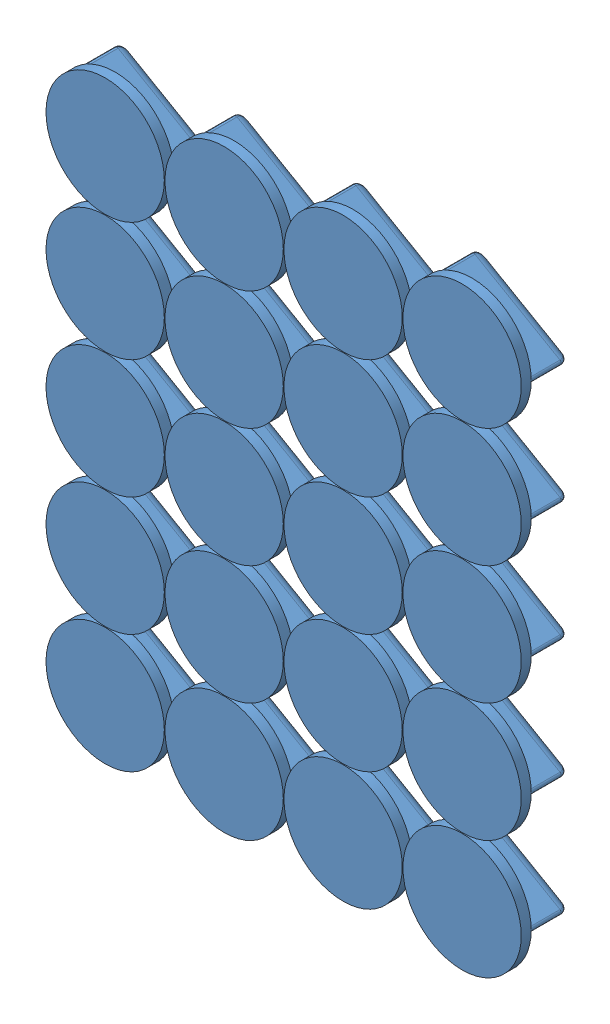
SolidWorks assembly Impression des bouton triangle, configuration Défaut. Lengths in mm.
Overall size (64.88 59.43 5).
20 component instances, 1 part files, 0 mates.
Components (placement in the parent):
- BoutonV2_PourImpression-1: BoutonV2_PourImpression [Default] at (-46.1693 10.9787 -2.5) size (19 11.83 5)
- BoutonV2_PourImpression-2: BoutonV2_PourImpression [Default] at (-46.1693 -0.9213 -2.5) size (19 11.83 5)
- BoutonV2_PourImpression-3: BoutonV2_PourImpression [Default] at (-46.1693 -12.8213 -2.5) size (19 11.83 5)
- BoutonV2_PourImpression-4: BoutonV2_PourImpression [Default] at (-46.1693 -24.7213 -2.5) size (19 11.83 5)
- BoutonV2_PourImpression-5: BoutonV2_PourImpression [Default] at (-46.1693 -36.6213 -2.5) size (19 11.83 5)
- BoutonV2_PourImpression-6: BoutonV2_PourImpression [Default] at (-58.0693 -36.6213 -2.5) size (19 11.83 5)
- BoutonV2_PourImpression-7: BoutonV2_PourImpression [Default] at (-69.9693 -36.6213 -2.5) size (19 11.83 5)
- BoutonV2_PourImpression-8: BoutonV2_PourImpression [Default] at (-81.8693 -36.6213 -2.5) size (19 11.83 5)
- BoutonV2_PourImpression-9: BoutonV2_PourImpression [Default] at (-58.0693 10.9787 -2.5) size (19 11.83 5)
- BoutonV2_PourImpression-10: BoutonV2_PourImpression [Default] at (-69.9693 10.9787 -2.5) size (19 11.83 5)
- BoutonV2_PourImpression-11: BoutonV2_PourImpression [Default] at (-81.8693 10.9787 -2.5) size (19 11.83 5)
- BoutonV2_PourImpression-12: BoutonV2_PourImpression [Default] at (-58.0693 -24.7213 -2.5) size (19 11.83 5)
- BoutonV2_PourImpression-13: BoutonV2_PourImpression [Default] at (-69.9693 -24.7213 -2.5) size (19 11.83 5)
- BoutonV2_PourImpression-14: BoutonV2_PourImpression [Default] at (-81.8693 -24.7213 -2.5) size (19 11.83 5)
- BoutonV2_PourImpression-15: BoutonV2_PourImpression [Default] at (-58.0693 -12.8213 -2.5) size (19 11.83 5)
- BoutonV2_PourImpression-16: BoutonV2_PourImpression [Default] at (-69.9693 -12.8213 -2.5) size (19 11.83 5)
- BoutonV2_PourImpression-17: BoutonV2_PourImpression [Default] at (-81.8693 -12.8213 -2.5) size (19 11.83 5)
- BoutonV2_PourImpression-18: BoutonV2_PourImpression [Default] at (-58.0693 -0.9213 -2.5) size (19 11.83 5)
- BoutonV2_PourImpression-19: BoutonV2_PourImpression [Default] at (-69.9693 -0.9213 -2.5) size (19 11.83 5)
- BoutonV2_PourImpression-20: BoutonV2_PourImpression [Default] at (-81.8693 -0.9213 -2.5) size (19 11.83 5)
